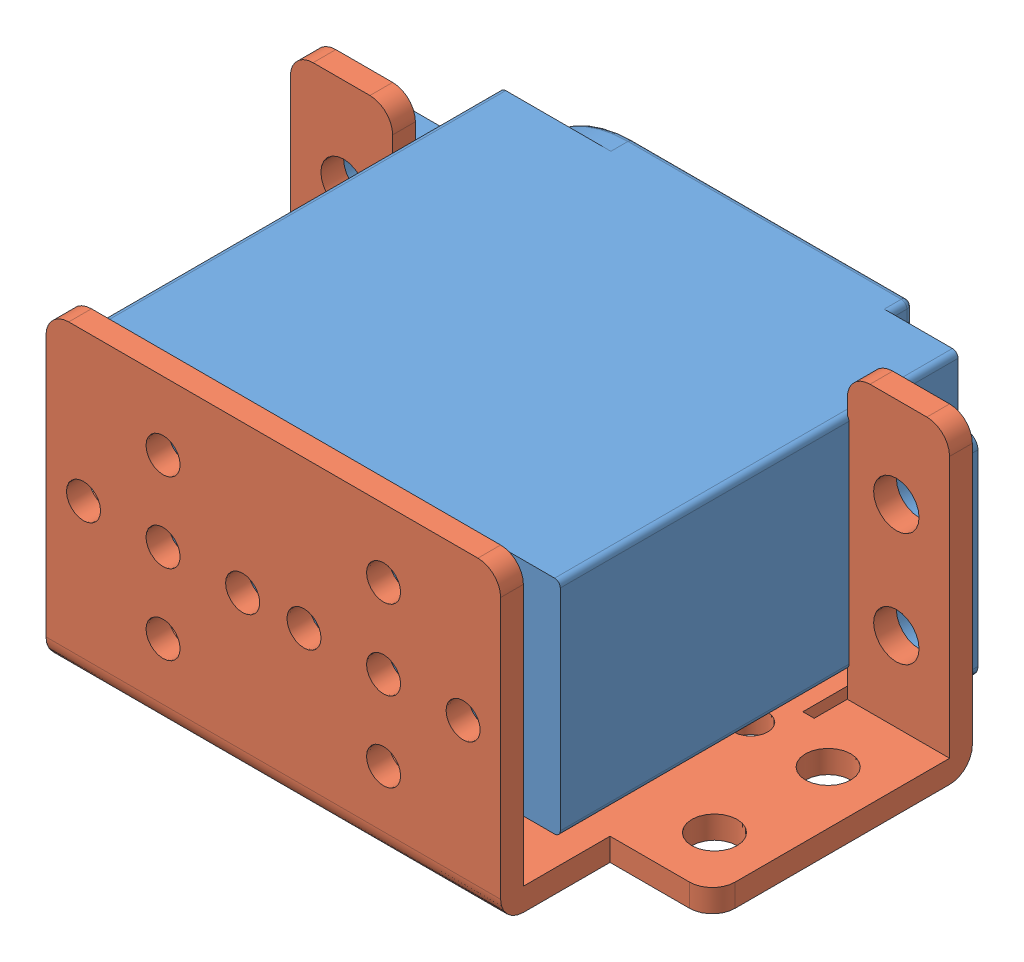
SolidWorks assembly 舵机与支架装配图（正装）, configuration 默认. Lengths in mm.
Overall size (58 27 48.1).
2 component instances, 2 part files, 3 mates.
Components (placement in the parent):
- MG995舵机-1: MG995舵机 [默认] at (-17.2384 9.9205 0) size (54 19.5 43)
- 舵机支架-1: 舵机支架 [默认] at (-5.7243 -13.1161 19.35) x (1 0 0) z (0 1 0) size (58 39.5 27)
Mates (geometry in assembly coordinates):
- 同心5: concentric anti-aligned: circle of MG995舵机-1; circle of 舵机支架-1
- 重合1: coincident anti-aligned: plane of MG995舵机-1 through (-32.7243 -8.3661 7.6) normal (0 0 1); plane of 舵机支架-1 through (-32.7243 11.8839 7.6) normal (0 0 -1)
- 同心6: concentric anti-aligned: circle of MG995舵机-1; circle of 舵机支架-1
